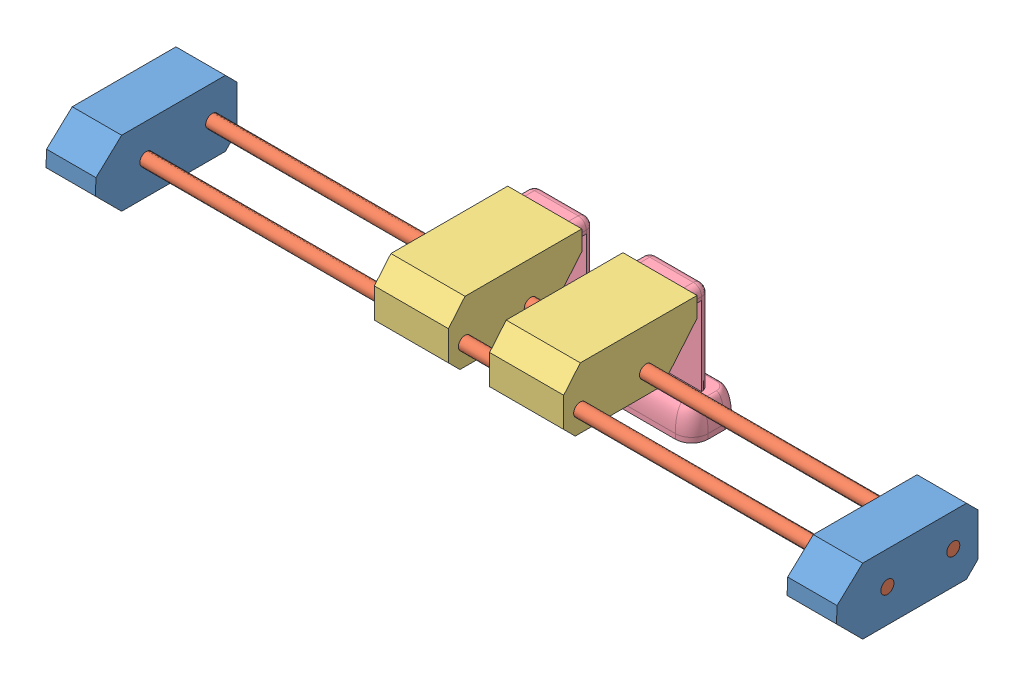
SolidWorks assembly M03, configuration Valor predeterminado. Lengths in mm.
Overall size (480 74.25 125.32).
8 component instances, 4 part files, 15 mates.
Components (placement in the parent):
- S03-1: S03 [Valor predeterminado] at (13.5401 19.4326 80.2659) size (30 40 87.32)
- B01-1: B01 [Valor predeterminado] at (-211.4599 19.4326 60.2659) x (0 -0.924225 -0.381849) z (1 0 0) size (7.94 7.94 480)
- B01-2: B01 [Valor predeterminado] at (-211.4599 19.4326 100.2659) x (0 -0.924225 -0.381849) z (1 0 0) size (7.94 7.94 480)
- S03-2: S03 [Valor predeterminado] at (-436.4599 19.4326 80.2659) size (30 40 87.32)
- S05-1: S05 [Valor predeterminado] at (-250.5177 19.4326 80.2659) x (0 0 -1) z (1 0 0) size (80.98 37 45)
- S05-2: S05 [Valor predeterminado] at (-180.5177 19.4326 80.2659) x (0 0 -1) z (1 0 0) size (80.98 37 45)
- C01-1: C01 [Valor predeterminado] at (-188.2677 -12.3174 22.2884) x (-1 0 0) z (0 -1 0) size (70.05 47.02 73)
- C01-2: C01 [Valor predeterminado] at (-258.2677 -12.3174 22.2884) x (-1 0 0) z (0 -1 0) size (70.05 47.02 73)
Mates (geometry in assembly coordinates):
- Coincidente1: coincident: circle of S03-1; circle of B01-1
- Coincidente2: coincident: circle of S03-1; circle of B01-2
- Coincidente3: coincident: circle of B01-1; circle of S03-2
- Coincidente4: coincident: circle of B01-2; circle of S03-2
- Concêntrico2: concentric: cylinder of B01-2 through (28.5401 19.4326 100.2659) axis (-1 0 0) radius 3.97; cylinder of S05-1 through (-228.0177 19.4326 100.2659) axis (-1 0 0) radius 3.97
- Concêntrico3: concentric: cylinder of B01-1 through (28.5401 19.4326 60.2659) axis (-1 0 0) radius 3.97; cylinder of S05-1 through (-228.0177 19.4326 60.2659) axis (-1 0 0) radius 3.97
- Concêntrico4: concentric: cylinder of B01-2 through (28.5401 19.4326 100.2659) axis (-1 0 0) radius 3.97; cylinder of S05-2 through (-158.0177 19.4326 100.2659) axis (-1 0 0) radius 3.97
- Concêntrico5: concentric: cylinder of B01-1 through (28.5401 19.4326 60.2659) axis (-1 0 0) radius 3.97; cylinder of S05-2 through (-158.0177 19.4326 60.2659) axis (-1 0 0) radius 3.97
- Coincidente5: coincident: line of S05-2 through (-198.7677 42.6826 54.2884) axis (1 0 0); line of C01-1 through (-167.2677 42.6826 54.2884) axis (-1 0 0)
- Coincidente6: coincident: plane of S05-2 through (-198.7677 42.6826 54.2884) normal (0 -1 0); plane of C01-1 through (-188.2677 42.6826 22.2884) normal (0 1 0)
- Coincidente7: coincident: plane of S05-2 through (-162.2677 33.1826 54.2884) normal (-1 0 0); plane of C01-1 through (-162.2677 42.6826 54.2884) normal (1 0 0)
- Coincidente8: coincident: plane of S05-1 through (-268.7677 42.6826 54.2884) normal (0 -1 0); plane of C01-2 through (-258.2677 42.6826 22.2884) normal (0 1 0)
- Coincidente9: coincident: line of S05-1 through (-268.7677 42.6826 54.2884) axis (1 0 0); line of C01-2 through (-237.2677 42.6826 54.2884) axis (-1 0 0)
- Coincidente10: coincident: plane of S05-1 through (-268.7677 33.1826 54.2884) normal (1 0 0); plane of C01-2 through (-268.7677 42.6826 54.2884) normal (-1 0 0)
- Coincidente11: coincident: line of C01-1 through (-223.2677 -30.3174 27.2884) axis (0 0 -1); line of C01-2 through (-223.2677 -30.3174 17.2884) axis (0 0 1)
